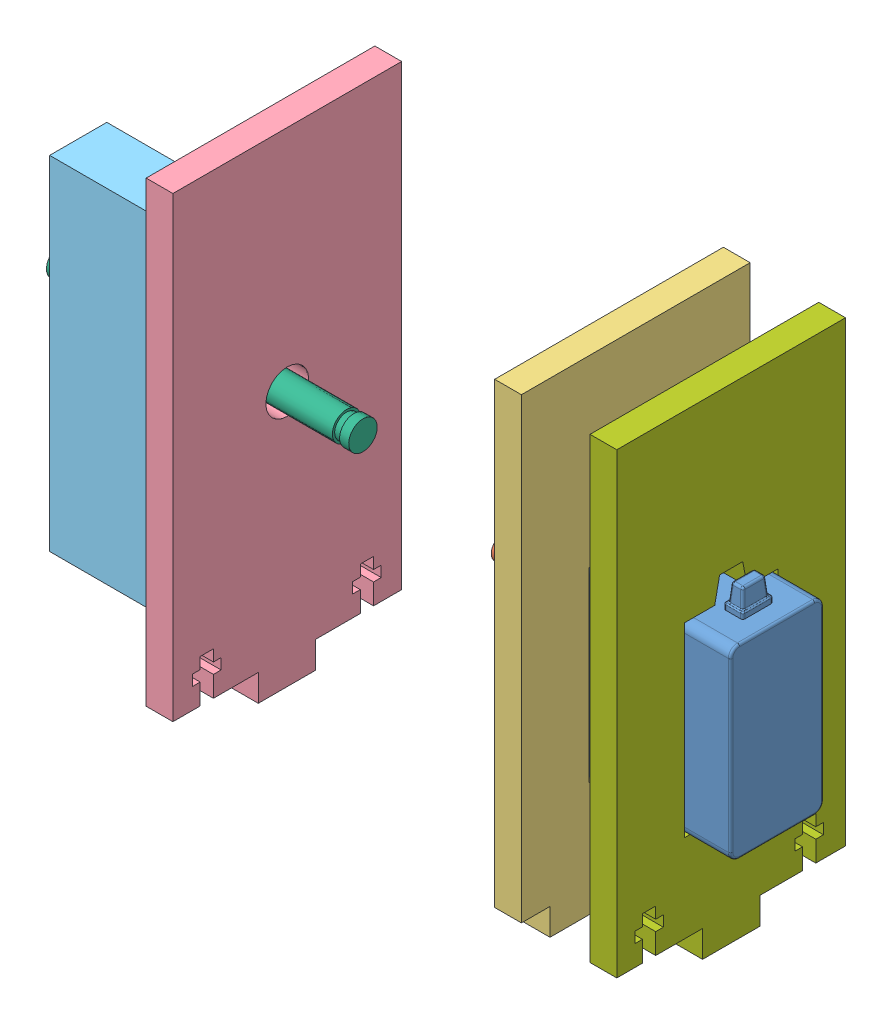
SolidWorks assembly SupportAssem, configuration Default. Lengths in mm.
Overall size (159.12 107.54 50.8).
7 component instances, 7 part files, 17 mates.
Components (placement in the parent):
- Servo SpringRC Rev1-1: Servo SpringRC Rev1 [Default] at (-74.825 -21.7734 20.8739) size (46.2 55.75 20.86)
- hs-422_horn_2wings_sws-4: hs-422_horn_2wings_sws [Default] at (-80.825 9.5266 31.2239) x (0 0.883679 -0.468092) z (0 0.468092 0.883679) size (9.1 5 34)
- Support1-1: Support1 [Default] at (-71.9686 -41.2734 56.6239) x (0 0 -1) z (1 0 0) size (50.8 107.54 5.94)
- Support2-1: Support2 [Default] at (-149.3716 -41.2734 5.8239) x (0 1 0) z (1 0 0) size (107.54 50.8 5.94)
- Scoop shaft support-1: Scoop shaft support [Default] at (-151.7578 -41.2734 12.1739) x (-1 0 0) z (0 0 -1) size (38.1 76.2 25.4)
- 2 inch shaft-1: 2 inch shaft [Default] at (-189.8578 9.5266 31.2239) x (0 0.432014 -0.901867) z (1 0 0) size (6.35 6.35 67.13)
- Support3-1: Support3 [Default] at (-50.785 -41.2734 5.8239) x (0 0 -1) z (1 0 0) size (50.8 107.54 5.94)
Mates (geometry in assembly coordinates):
- Concentric2: concentric: cylinder of Servo SpringRC Rev1-1 through (-80.825 9.5266 31.2239) axis (1 0 0) radius 3; cylinder of hs-422_horn_2wings_sws-4 through (-78.325 9.5266 31.2239) axis (-1 0 0) radius 2.5
- Coincident2: coincident: plane of Servo SpringRC Rev1-1 through (-80.825 9.5266 31.2239) normal (-1 0 0); plane of hs-422_horn_2wings_sws-4 through (-80.825 2.7393 18.4105) normal (1 0 0)
- Coincident5: coincident: plane of Servo SpringRC Rev1-1 through (-66.025 26.7516 20.8739) normal (-1 0 0); plane of Support1-1 through (-66.025 -41.2734 56.6239) normal (1 0 0)
- Parallel3: parallel: plane of Support1-1 through (-71.9686 -41.2734 56.6239) normal (-1 0 0); plane of Support2-1 through (-143.428 -41.2734 5.8239) normal (1 0 0)
- Parallel4: parallel: plane of Support1-1 through (-66.025 60.3266 56.6239) normal (0 1 0); plane of Support2-1 through (-143.428 60.3266 5.8239) normal (0 1 0)
- Concentric6: concentric: circle of Support2-1; circle of Scoop shaft support-1
- Coincident21: coincident: plane of Support2-1 through (-143.428 -41.2734 5.8239) normal (0 -1 0); plane of Scoop shaft support-1 through (-189.8578 -41.2734 12.1739) normal (0 -1 0)
- Concentric7: concentric: circle of Support2-1; circle of 2 inch shaft-1
- Concentric8: concentric: circle of hs-422_horn_2wings_sws-4; circle of Support2-1
- Coincident24: coincident: plane of Support2-1 through (-143.428 -41.2734 5.8239) normal (0 -1 0); plane of Support1-1 through (-66.025 -41.2734 56.6239) normal (0 -1 0)
- Parallel7: parallel: cylinder of Servo SpringRC Rev1-1 through (-74.325 19.5266 41.0739) axis (0 -1 0) radius 0.5; line of Support1-1 through (-71.9686 60.3266 56.6239) axis (0 -1 0)
- Coincident28: coincident: plane of Scoop shaft support-1 through (-189.8578 -41.2734 12.1739) normal (-1 0 0); plane of 2 inch shaft-1 through (-189.8578 9.5266 31.2239) normal (-1 0 0)
- Coincident29: coincident: plane of Support1-1 through (-66.025 -41.2734 5.8239) normal (0 0 -1); plane of Support2-1 through (-143.428 -41.2734 5.8239) normal (0 0 -1)
- Coincident30: coincident: plane of Support1-1 through (-66.025 -41.2734 56.6239) normal (0 0 1); plane of Support2-1 through (-143.428 -41.2734 56.6239) normal (0 0 1)
- Coincident31: coincident: plane of Support1-1 through (-66.025 -41.2734 56.6239) normal (0 -1 0); plane of Support3-1 through (-44.8414 -41.2734 37.5739) normal (0 -1 0)
- Distance1: distance = 15.24 mm: plane of Support1-1 through (-66.025 -41.2734 56.6239) normal (1 0 0); plane of Support3-1 through (-50.785 -41.2734 5.8239) normal (-1 0 0)
- Coincident36: coincident: plane of Support1-1 through (-66.025 -41.2734 56.6239) normal (0 0 1); plane of Support3-1 through (-44.8414 -41.2734 56.6239) normal (0 0 1)
